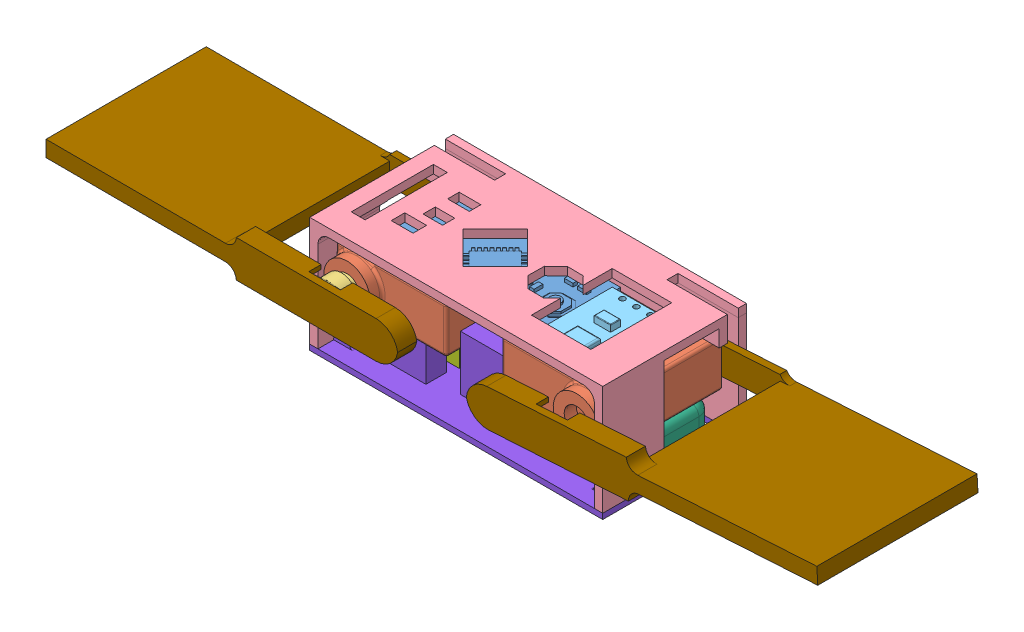
SolidWorks assembly Smarticle- Assembly, configuration Default. Lengths in mm.
Overall size (371.41 21.05 192.23).
15 component instances, 9 part files, 21 mates.
Components (placement in the parent):
- Arduino Pro Mini-1: Arduino Pro Mini [Varsayılan] at (11.3668 -0.6942 -27.9476) size (331.39 1.8 192.23)
- Servo - Assembly-1: Servo - Assembly [Default] at (119.2246 26.3366 -44.2097) x (1 0 0) z (0 -1 0) size (29.6 26.5 8.7) (flexible)
  - Servo - Body-1: Servo - Body [Default] at (-78.8577 -3.7379 27.0308) size (20.3 22.2 8.7)
  - Servo - Horn-1: Servo - Horn [Default] at (-62.9077 22.0121 31.2808) x (0.998229 0 -0.059489) z (0.059489 0 0.998229) size (27 6.5 5.75) (hidden)
- Servo - Assembly-2: Servo - Assembly [Default] at (-48.4909 -36.2251 -44.2097) x (-1 0 0) z (0 1 0) size (29.46 26.5 8.7) (flexible)
  - Servo - Body-1: Servo - Body [Default] at (-78.8577 -3.7379 27.0308) size (20.3 22.2 8.7)
  - Servo - Horn-1: Servo - Horn [Default] at (-62.9077 22.0121 31.2808) x (0.999997 0 0.002372) z (-0.002372 0 0.999997) size (27 6.5 5.75)
- Case-1: Case [Default] at (8.6669 3.8558 -50.9476) x (1 0 0) z (0 -1 0) size (53.48 26.25 20.05)
- Microphone-1: Microphone [Default] at (56.3851 -0.6942 310.2103) x (0 0 1) z (-1 0 0) size (14.75 2.8 10.85)
- Battery - Assembly-1: Battery - Assembly [Default] at (5.3934 4.5627 -34.4908) x (-1 0 0) z (0 -1 0) size (44.5 12.25 6.25)
  - Battery - Body-1: Battery - Body [Default] at (-55.7734 -0.4976 13.7569) size (36.5 11.75 5.5)
  - Battery - Connector-1: Battery - Connector [Default] at (-19.2734 -0.7476 14.4069) size (10.25 12.25 5.6)
- Battery Back-1: Battery Back [Default] at (-152.2376 -17.1942 -37.0166) size (53.48 11 26.25)
- Servo - Solar Arm-2: Servo - Solar Arm [Default] at (14.511 -8.3195 -20.1976) x (-0.999997 0.002372 0) z (0 0 -1) size (64.2 6.75 30.75)
- Servo - Solar Arm-3: Servo - Solar Arm [Default] at (56.218 -1.5691 -20.1976) x (0.998229 0.059489 0) z (0 0 -1) size (64.2 6.75 30.75)
Mates (geometry in assembly coordinates):
- Coincident5: coincident aligned: plane of Servo - Assembly-1/Servo - Body-1 through (40.3669 -0.6942 -47.9476) normal (0 1 0); plane of Servo - Assembly-2/Servo - Body-1 through (30.3669 -0.6942 -47.9476) normal (0 1 0)
- Coincident6: coincident aligned: plane of Servo - Assembly-1/Servo - Body-1 through (40.3669 -9.1942 -27.9476) normal (0 0 1); plane of Servo - Assembly-2/Servo - Body-1 through (30.3669 -0.6942 -27.9476) normal (0 0 1)
- Coincident19: coincident anti-aligned: plane of Arduino Pro Mini-1 through (44.3668 0.1058 -27.9476) normal (1 0 0); plane of Microphone-1 through (44.3668 0.9058 -44.2226) normal (-1 0 0)
- Coincident20: coincident anti-aligned: plane of Servo - Assembly-1/Servo - Body-1 through (40.3669 -0.6942 -47.9476) normal (0 1 0); plane of Microphone-1 through (56.3851 -0.6942 310.2103) normal (0 -1 0)
- Parallel1: parallel anti-aligned: plane of Case-1 through (8.6669 -69.6999 -49.4476) normal (0 0 1); plane of Battery - Assembly-1/Battery - Connector-1 through (24.6669 -15.4442 -45.9932) normal (0 0 -1)
- Coincident23: coincident anti-aligned: plane of Servo - Assembly-2/Servo - Body-1 through (10.1669 -0.6942 -47.9476) normal (-1 0 0); plane of Case-1 through (10.1669 -29.027 -24.6976) normal (1 0 0)
- Distance1: distance = 1.5 mm anti-aligned: plane of Servo - Assembly-1/Servo - Body-1 through (40.3669 -9.1942 -47.9476) normal (0 0 -1); plane of Case-1 through (8.6669 -69.6999 -49.4476) normal (0 0 1)
- Coincident29: coincident anti-aligned: plane of Servo - Assembly-2/Servo - Horn-1 through (14.4169 -4.9442 -21.4476) normal (0 0 1); plane of Servo - Solar Arm-2 through (14.511 -8.3195 -21.4476) normal (0 0 -1)
- Width3: width aligned: plane of Servo - Solar Arm-2 through (13.9035 -2.1306 -23.6976) normal (0.097687 -0.995217 0); plane of Servo - Solar Arm-2 through (14.5619 -7.8246 -23.6976) normal (0.102407 0.994743 0); plane of Servo - Assembly-2/Servo - Horn-1 through (14.1181 -7.7886 -21.4476) normal (-0.104467 -0.994528 0); plane of Servo - Assembly-2/Servo - Horn-1 through (14.1316 -2.0985 -21.4476) normal (-0.099748 0.995013 0)
- Coincident30: coincident anti-aligned: plane of Case-1 through (61.1669 -16.1942 -33.9932) normal (0 -1 0); plane of Battery Back-1 through (-152.2376 -16.1942 -37.0166) normal (0 1 0)
- Coincident31: coincident aligned: plane of Case-1 through (62.1515 2.3558 -50.9476) normal (1 0 0); plane of Battery Back-1 through (62.1515 -16.1942 -24.6976) normal (1 0 0)
- Coincident32: coincident aligned: plane of Case-1 through (8.6669 -69.6999 -50.9476) normal (0 0 -1); plane of Battery Back-1 through (8.6669 -16.1942 -50.9476) normal (0 0 -1)
- Coincident33: coincident anti-aligned: plane of Servo - Assembly-1/Servo - Body-1 through (40.3669 -9.1942 -47.9476) normal (0 -1 0); plane of Battery - Assembly-1/Battery - Body-1 through (61.1669 -9.1942 -33.9932) normal (0 1 0)
- Distance3: distance = 2.25 mm anti-aligned: plane of Arduino Pro Mini-1 through (11.3668 0.1058 -27.9476) normal (0 1 0); plane of Case-1 through (8.6669 2.3558 -50.9476) normal (0 -1 0)
- Symmetric2: symmetric aligned: cylinder of Servo - Solar Arm-2 through (2.419 -4.9158 -23.6976) axis (0 0 1) radius 1.65; cylinder of Servo - Solar Arm-2 through (26.6189 -4.9732 -23.6976) axis (0 0 1) radius 1.65; plane of assembly through (14.5306 -0.0345 0) normal (-0.999997 0.002372 0)
- Coincident35: coincident anti-aligned: plane of Servo - Assembly-1/Servo - Horn-1 through (56.3169 -4.9442 -21.4476) normal (0 0 1); plane of Servo - Solar Arm-3 through (56.218 -1.5691 -21.4476) normal (0 0 -1)
- Width5: width anti-aligned: plane of Servo - Assembly-1/Servo - Horn-1 through (56.7776 -7.7668 -21.4476) normal (0.161104 -0.986937 0); plane of Servo - Assembly-1/Servo - Horn-1 through (56.4391 -2.0869 -21.4476) normal (0.042749 0.999086 0); plane of Servo - Solar Arm-3 through (57.2072 -7.7086 -23.6976) normal (-0.15906 0.987269 0); plane of Servo - Solar Arm-3 through (56.1978 -2.0662 -23.6976) normal (-0.04068 -0.999172 0)
- Symmetric5: symmetric aligned: cylinder of Servo - Solar Arm-3 through (44.3402 -5.658 -23.6976) axis (0 0 1) radius 1.65; cylinder of Servo - Solar Arm-3 through (68.4974 -4.2183 -23.6976) axis (0 0 1) radius 1.65; plane of assembly through (55.9259 3.3329 0) normal (-0.998229 -0.059489 0)
- Distance4: distance = 10 mm anti-aligned: plane of Servo - Assembly-1/Servo - Body-1 through (40.3669 -9.1942 -47.9476) normal (-1 0 0); plane of Servo - Assembly-2/Servo - Body-1 through (30.3669 -0.6942 -47.9476) normal (1 0 0)
- Width6: width anti-aligned: plane of Microphone-1 through (44.3668 0.9058 -44.2226) normal (0 0 -1); plane of Microphone-1 through (44.3668 0.9058 -29.4726) normal (0 0 1); plane of Arduino Pro Mini-1 through (11.3668 0.1058 -27.9476) normal (0 0 1); plane of Arduino Pro Mini-1 through (11.3668 0.1058 -45.7476) normal (0 0 -1)
- Coincident37: coincident aligned: plane of Battery - Assembly-1/Battery - Connector-1 through (19.6669 -15.4442 -33.7432) normal (-1 0 0); plane of Battery Back-1 through (19.6669 -11.4432 -47.4476) normal (-1 0 0)
